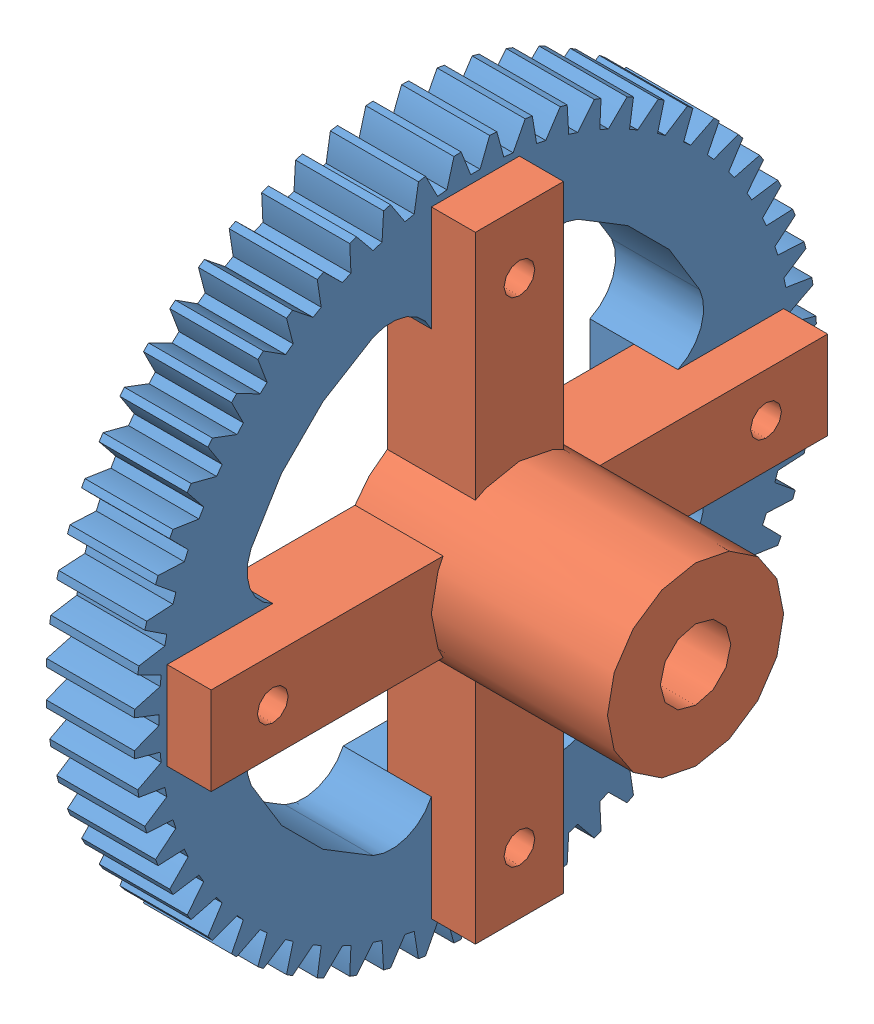
SolidWorks assembly Сборка2, configuration По умолчанию. Lengths in mm.
Overall size (35 77.43 77.43).
2 component instances, 2 part files, 3 mates.
Components (placement in the parent):
- Колесо зубчатое m1.25_z60_b10-1: Колесо зубчатое m1.25_z60_b10 [По умолчанию] at origin size (10 77.43 77.43)
- Ступица выходного колеса-1: Ступица выходного колеса [По умолчанию] at (-18.6066 1.4674 22.1395) x (0 0 -1) z (1 0 0) size (70 70 30)
Mates (geometry in assembly coordinates):
- Концентричный1: concentric: cylinder of Колесо зубчатое m1.25_z60_b10-1 through (-13.6066 29.4674 22.1395) axis (1 0 0) radius 1.75; cylinder of Ступица выходного колеса-1 through (4.8732 29.4674 22.1395) axis (-1 0 0) radius 1.75
- Концентричный4: concentric: cylinder of Колесо зубчатое m1.25_z60_b10-1 through (-13.6066 -26.5326 22.1395) axis (1 0 0) radius 1.75; cylinder of Ступица выходного колеса-1 through (-13.6066 -26.5326 22.1395) axis (-1 0 0) radius 1.75
- Совпадение1: coincident anti-aligned: plane of Колесо зубчатое m1.25_z60_b10-1 through (-13.6066 1.4674 22.1395) normal (1 0 0); plane of Ступица выходного колеса-1 through (-13.6066 1.4674 22.1395) normal (-1 0 0)
